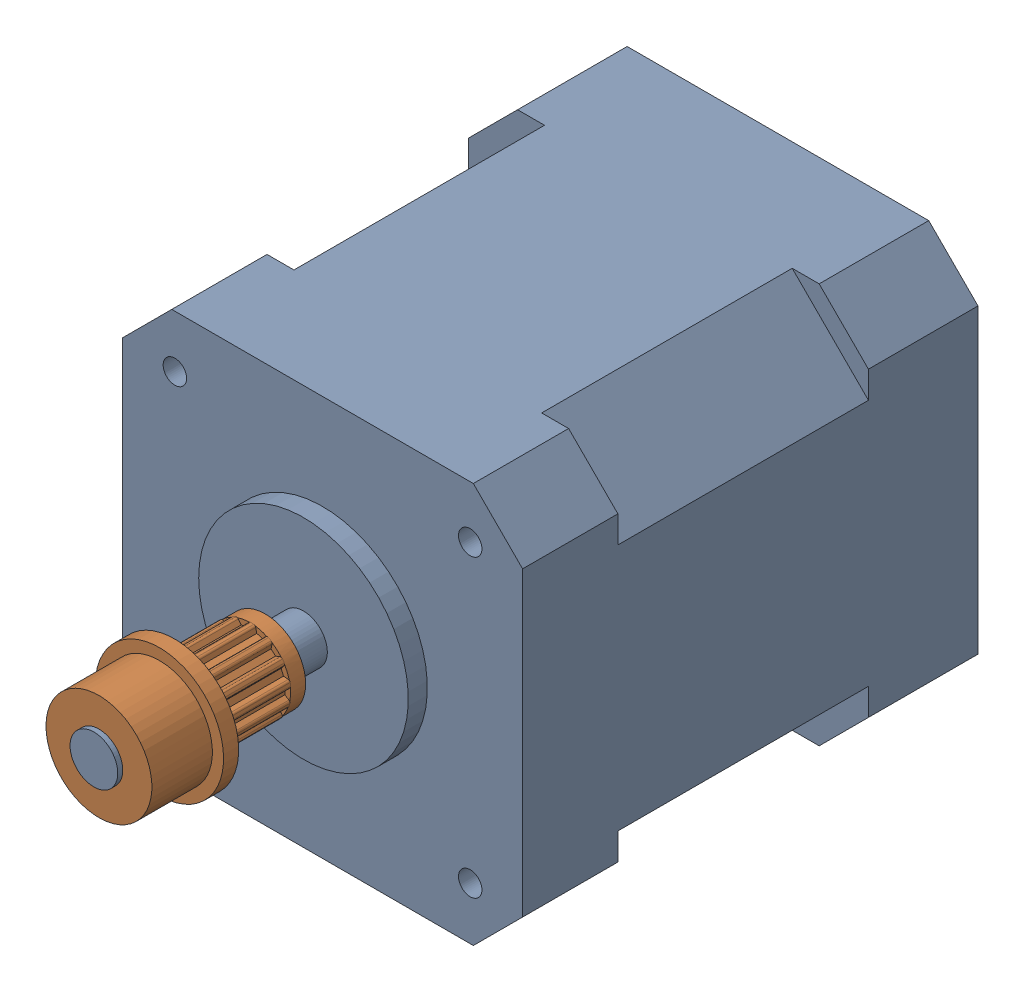
SolidWorks assembly stepper-with-gear, configuration Default. Lengths in mm.
Overall size (52 42 71.8).
2 component instances, 2 part files, 1 mates.
Components (placement in the parent):
- nema-17-stepper-1: nema-17-stepper [Default] at (50.0067 -46.8574 -86.3573) size (52 42 71.8)
- mxl-pulley-14tooth-1: mxl-pulley-14tooth [Default] at (50.0067 -46.8574 -26.992) x (0.386693 -0.922208 0) z (0 0 1) size (13.46 13.46 17.46)
Mates (geometry in assembly coordinates):
- Concentric1: concentric: cylinder of nema-17-stepper-1; cylinder of mxl-pulley-14tooth-1
